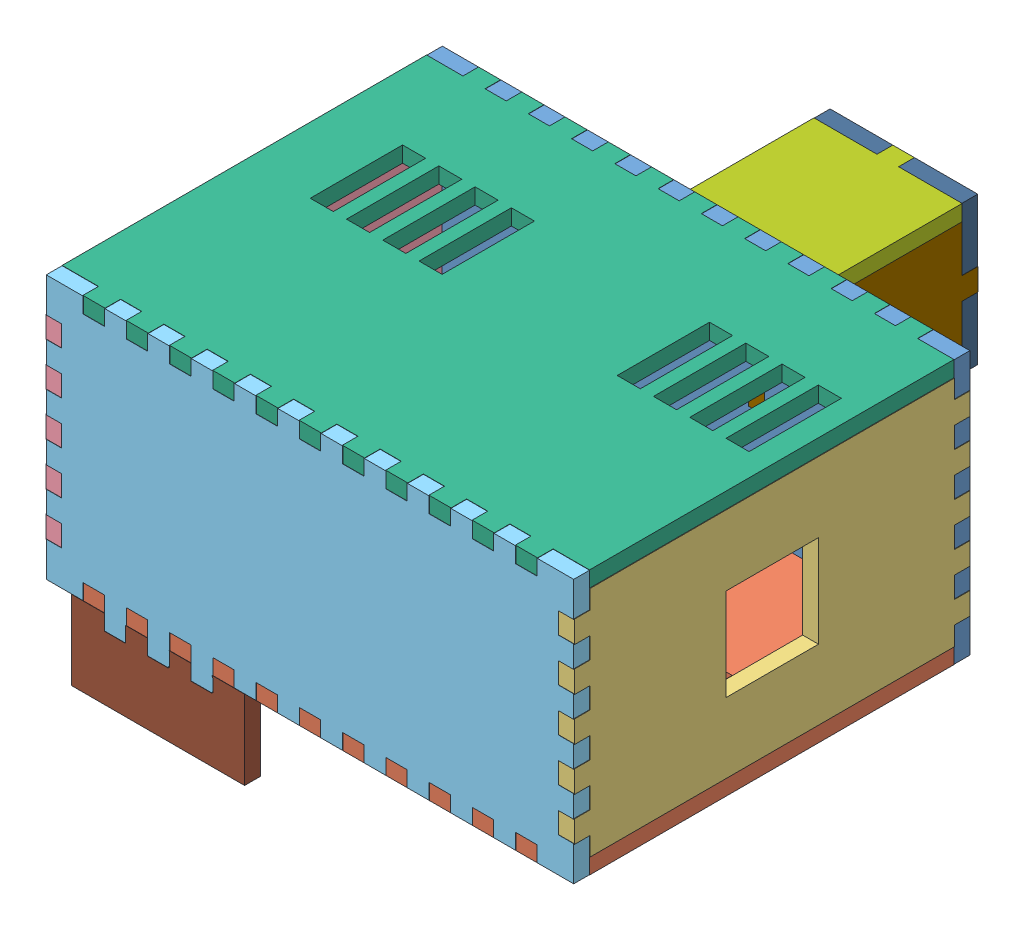
SolidWorks assembly House, configuration Default. Lengths in mm.
Overall size (273.64 363.29 275.23).
13 component instances, 12 part files, 37 mates.
Components (placement in the parent):
- House_base_x_1-1: House_base_x_1 [Default] at (28.0784 -108.1405 -199.323) x (1 0 0) z (0 -1 0) size (200 6 100)
- House Front wall_x_1-1: House Front wall_x_1 [Default] at (-5.7208 -102.2405 -49.223) x (-0.437688 0.786948 0.434904) z (0.068976 0.511658 -0.856416) size (152.36 219.82 143.42)
- Copy of House Left wall_x_1-1: Copy of House Left wall_x_1 [Default] at (222.2784 -166.4172 -23.0483) x (0 1 0) z (1 0 0) size (127.92 239.25 6)
- House Right wall_x_1-1: House Right wall_x_1 [Default] at (27.8784 -166.3172 -23.0483) x (0 1 0) z (1 0 0) size (127.92 239.25 6)
- House_top_x_1-1: House_top_x_1 [Default] at (28.0784 -108.1405 -55.123) x (1 0 0) z (0 -1 0) size (200 6 105.9)
- House Back wall_x_1-1: House Back wall_x_1 [Default] at (261.8775 -8.0405 -199.223) x (0.437688 0.786948 -0.434904) z (-0.068976 0.511658 0.856416) size (152.36 219.82 143.42)
- Terrace_wall_x_2-1: Terrace_wall_x_2 [Default] at (99.9784 -36.2405 -193.323) size (56.2 6 81)
- Terrace_wall_x_2-2: Terrace_wall_x_2 [Default] at (99.9784 -86.0405 -193.323) size (56.2 6 81)
- Terrace_front_x_1-1: Terrace_front_x_1 [Default] at (99.9784 -36.0405 -193.323) x (0 -1 0) z (0 0 1) size (44.2 6 81)
- Terrace_wall_back_x_1-1: Terrace_wall_back_x_1 [Default] at (150.1784 -33.0405 -193.323) x (0 -1 0) z (0 0 1) size (50.2 6 81)
- Terrace_top_x_1-1: Terrace_top_x_1 [Default] at (156.0784 -86.2405 -268.323) x (0 0 -1) z (1 0 0) size (6 56 56)
- House step_1_x_1-1: House step_1_x_1 [Default] at (37.6784 -138.2405 -55.123) size (65.6 30 6)
- House step_2_x_1-2: House step_2_x_1 [Default] at (46.8893 -108.2405 -55.123) x (1 0 0) z (0 1 0) size (50 6 20)
Mates (geometry in assembly coordinates):
- Coincident19: coincident anti-aligned: plane of House_base_x_1-1 through (42.0784 -102.2405 93.7861) normal (0 -1 0); plane of House Front wall_x_1-1 through (-5.7208 -102.2405 -49.223) normal (0 1 0)
- Coincident20: coincident anti-aligned: plane of House_base_x_1-1 through (28.0784 -108.1405 -193.323) normal (0 0 1); plane of House Front wall_x_1-1 through (58.2784 -494.9286 -193.323) normal (0 0 -1)
- Width2: width anti-aligned: plane of House Front wall_x_1-1 through (50.2784 -494.9286 -193.323) normal (1 0 0); plane of House Front wall_x_1-1 through (41.8784 -494.9286 -199.223) normal (-1 0 0); plane of House_base_x_1-1 through (50.0784 -102.2405 93.7861) normal (-1 0 0); plane of House_base_x_1-1 through (42.0784 -108.1405 93.7861) normal (1 0 0)
- Coincident29: coincident anti-aligned: plane of House_base_x_1-1 through (28.0784 -108.1405 -193.323) normal (0 0 1); plane of Copy of House Left wall_x_1-1 through (4.6375 -21.1405 -193.323) normal (0 0 -1)
- Coincident30: coincident anti-aligned: plane of House_base_x_1-1 through (222.2784 -21.3405 86.2861) normal (1 0 0); plane of Copy of House Left wall_x_1-1 through (222.2784 -166.4172 -23.0483) normal (-1 0 0)
- Width4: width anti-aligned: plane of Copy of House Left wall_x_1-1 through (4.6375 -95.1405 -193.323) normal (0 -1 0); plane of Copy of House Left wall_x_1-1 through (4.6375 -86.7405 -199.223) normal (0 1 0); plane of House_base_x_1-1 through (222.2784 -94.9405 93.7861) normal (0 1 0); plane of House_base_x_1-1 through (228.0784 -86.9405 93.7861) normal (0 -1 0)
- Coincident31: coincident anti-aligned: plane of House_base_x_1-1 through (33.8784 -21.3405 93.7861) normal (-1 0 0); plane of House Right wall_x_1-1 through (33.8784 -166.3172 -23.0483) normal (1 0 0)
- Coincident32: coincident anti-aligned: plane of House_base_x_1-1 through (28.0784 -108.1405 -193.323) normal (0 0 1); plane of House Right wall_x_1-1 through (-189.636 -21.1405 -193.323) normal (0 0 -1)
- Width5: width anti-aligned: plane of House Right wall_x_1-1 through (-189.636 -21.1405 -199.223) normal (0 1 0); plane of House Right wall_x_1-1 through (-189.636 -29.5405 -193.323) normal (0 -1 0); plane of House_base_x_1-1 through (28.0784 -21.3405 93.7861) normal (0 -1 0); plane of House_base_x_1-1 through (33.8784 -29.3405 93.7861) normal (0 1 0)
- Coincident34: coincident anti-aligned: plane of House Right wall_x_1-1 through (251.3927 -37.5405 -55.123) normal (0 0 1); plane of House_top_x_1-1 through (28.0784 -108.1405 -55.123) normal (0 0 -1)
- Width6: width aligned: plane of Copy of House Left wall_x_1-1 through (445.9193 -21.1405 -49.223) normal (0 1 0); plane of Copy of House Left wall_x_1-1 through (445.9193 -29.5405 -55.123) normal (0 -1 0); plane of House_top_x_1-1 through (222.2784 -29.3405 230.4861) normal (0 1 0); plane of House_top_x_1-1 through (228.0784 -21.3405 230.4861) normal (0 -1 0)
- Coincident36: coincident anti-aligned: plane of Copy of House Left wall_x_1-1 through (228.2784 -14.0405 -199.223) normal (0 1 0); plane of House Back wall_x_1-1 through (261.8775 -14.0405 -199.223) normal (0 -1 0)
- Width9: width aligned: plane of House Back wall_x_1-1 through (205.8784 382.4791 -199.223) normal (-1 0 0); plane of House Back wall_x_1-1 through (214.2784 382.4791 -193.323) normal (1 0 0); plane of House_base_x_1-1 through (214.0784 -14.0405 93.7861) normal (-1 0 0); plane of House_base_x_1-1 through (206.0784 -8.1405 93.7861) normal (1 0 0)
- Width10: width anti-aligned: plane of House Back wall_x_1-1 through (41.8784 -400.7286 -55.123) normal (-1 0 0); plane of House Back wall_x_1-1 through (50.2784 -400.7286 -49.223) normal (1 0 0); plane of House_top_x_1-1 through (42.0784 -8.1405 237.9861) normal (1 0 0); plane of House_top_x_1-1 through (50.0784 -14.0405 237.9861) normal (-1 0 0)
- Coincident37: coincident anti-aligned: plane of House_base_x_1-1 through (156.8784 -14.0405 93.7861) normal (0 1 0); plane of House Back wall_x_1-1 through (261.8775 -14.0405 -199.223) normal (0 -1 0)
- Coincident38: coincident anti-aligned: plane of House_base_x_1-1 through (28.0784 -108.1405 -193.323) normal (0 0 1); plane of House Back wall_x_1-1 through (41.8784 382.4791 -193.323) normal (0 0 -1)
- Coincident43: coincident anti-aligned: plane of House_base_x_1-1 through (28.0784 -108.1405 -199.323) normal (0 0 -1); plane of Terrace_wall_x_2-1 through (132.2784 87.1494 -199.323) normal (0 0 1)
- Parallel4: parallel aligned: plane of House Back wall_x_1-1 through (261.8775 -8.0405 -199.223) normal (0 1 0); plane of Terrace_wall_x_2-1 through (99.9784 -30.2405 -193.323) normal (0 1 0)
- Width11: width anti-aligned: plane of Terrace_wall_x_2-1 through (123.8784 94.6494 -193.323) normal (-1 0 0); plane of Terrace_wall_x_2-1 through (132.2784 87.1494 -193.323) normal (1 0 0); plane of House_base_x_1-1 through (124.0784 -36.0405 -199.323) normal (1 0 0); plane of House_base_x_1-1 through (132.0784 -36.0405 -199.323) normal (-1 0 0)
- Coincident45: coincident anti-aligned: plane of House_base_x_1-1 through (132.0784 -30.2405 -199.323) normal (0 -1 0); plane of Terrace_wall_x_2-1 through (99.9784 -30.2405 -193.323) normal (0 1 0)
- Coincident46: coincident anti-aligned: plane of House_base_x_1-1 through (28.0784 -108.1405 -199.323) normal (0 0 -1); plane of Terrace_wall_x_2-2 through (123.8784 44.8494 -199.323) normal (0 0 1)
- Coincident47: coincident anti-aligned: plane of House_base_x_1-1 through (132.0784 -86.0405 -199.323) normal (0 1 0); plane of Terrace_wall_x_2-2 through (99.9784 -86.0405 -193.323) normal (0 -1 0)
- Width12: width aligned: plane of Terrace_wall_x_2-2 through (123.8784 44.8494 -193.323) normal (-1 0 0); plane of Terrace_wall_x_2-2 through (132.2784 37.3494 -193.323) normal (1 0 0); plane of House_base_x_1-1 through (132.0784 -80.2405 -199.323) normal (-1 0 0); plane of House_base_x_1-1 through (124.0784 -80.2405 -199.323) normal (1 0 0)
- Coincident52: coincident anti-aligned: plane of House_base_x_1-1 through (28.0784 -108.1405 -199.323) normal (0 0 -1); plane of Terrace_front_x_1-1 through (215.0557 -62.3405 -199.323) normal (0 0 1)
- Coincident53: coincident anti-aligned: plane of House_base_x_1-1 through (105.9784 -62.1405 -199.323) normal (-1 0 0); plane of Terrace_front_x_1-1 through (105.9784 -36.0405 -193.323) normal (1 0 0)
- Width13: width aligned: plane of Terrace_front_x_1-1 through (215.0557 -62.3405 -193.323) normal (0 -1 0); plane of Terrace_front_x_1-1 through (222.5557 -53.9405 -193.323) normal (0 1 0); plane of House_base_x_1-1 through (100.1784 -54.1405 -199.323) normal (0 -1 0); plane of House_base_x_1-1 through (100.1784 -62.1405 -199.323) normal (0 1 0)
- Coincident54: coincident anti-aligned: plane of House_base_x_1-1 through (28.0784 -108.1405 -199.323) normal (0 0 -1); plane of Terrace_wall_back_x_1-1 through (276.7397 -53.9405 -199.323) normal (0 0 1)
- Coincident55: coincident anti-aligned: plane of Terrace_wall_back_x_1-1 through (150.1784 -33.0405 -193.323) normal (-1 0 0); plane of House_base_x_1-1 through (150.1784 -62.1405 -199.323) normal (1 0 0)
- Width14: width anti-aligned: plane of Terrace_wall_back_x_1-1 through (276.7397 -53.9405 -193.323) normal (0 1 0); plane of Terrace_wall_back_x_1-1 through (269.2397 -62.3405 -193.323) normal (0 -1 0); plane of House_base_x_1-1 through (155.9784 -54.1405 -199.323) normal (0 -1 0); plane of House_base_x_1-1 through (155.9784 -62.1405 -199.323) normal (0 1 0)
- Coincident56: coincident anti-aligned: plane of Terrace_wall_x_2-1 through (99.9784 -30.2405 -268.323) normal (0 0 -1); plane of Terrace_top_x_1-1 through (156.0784 -86.2405 -268.323) normal (0 0 1)
- Coincident57: coincident aligned: plane of Terrace_wall_x_2-1 through (99.9784 -30.2405 -193.323) normal (0 1 0); plane of Terrace_top_x_1-1 through (156.0784 -30.2405 -274.323) normal (0 1 0)
- Width15: width aligned: plane of Terrace_top_x_1-1 through (124.0784 -36.2405 -381.1017) normal (1 0 0); plane of Terrace_top_x_1-1 through (132.0784 -30.2405 -381.1017) normal (-1 0 0); plane of Terrace_wall_x_2-1 through (132.2784 -30.2405 -274.323) normal (1 0 0); plane of Terrace_wall_x_2-1 through (123.8784 -30.2405 -274.323) normal (-1 0 0)
- Coincident58: coincident anti-aligned: plane of House Front wall_x_1-1 through (-5.7208 -108.2405 -49.223) normal (0 -1 0); plane of House step_1_x_1-1 through (37.6784 -108.2405 -49.123) normal (0 1 0)
- Coincident59: coincident aligned: plane of House_top_x_1-1 through (28.0784 -108.1405 -49.123) normal (0 0 1); plane of House step_1_x_1-1 through (37.6784 -138.2405 -49.123) normal (0 0 1)
- Coincident60: coincident anti-aligned: plane of House_top_x_1-1 through (50.0784 -102.2405 237.9861) normal (-1 0 0); plane of House step_1_x_1-1 through (50.0784 -114.1405 -147.1023) normal (1 0 0)
- Coincident62: coincident anti-aligned: plane of House step_1_x_1-1 through (37.6784 -138.2405 -55.123) normal (0 0 -1); plane of House step_2_x_1-2 through (46.8893 -108.2405 -55.123) normal (0 0 1)
- Coincident63: coincident anti-aligned: plane of House Front wall_x_1-1 through (-5.7208 -108.2405 -49.223) normal (0 -1 0); plane of House step_2_x_1-2 through (46.8893 -108.2405 -61.123) normal (0 1 0)
